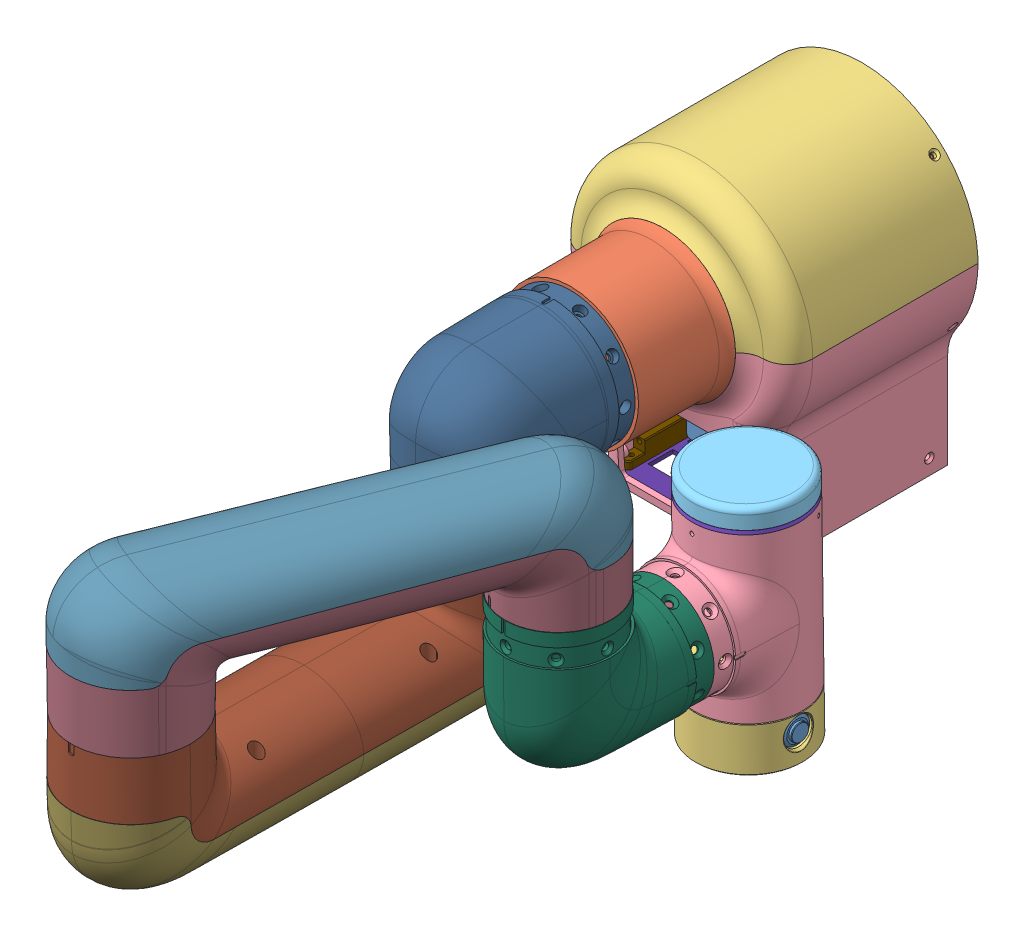
SolidWorks assembly PRO450包装版本, configuration 默认. Lengths in mm.
Overall size (276.89 209.51 434.16).
29 component instances, 22 part files, 10 mates.
Components (placement in the parent):
- J6末端^PRO450包装版本-1: J6末端^PRO450包装版本 [默认] at (339.7014 53.0863 383.1961) x (0.031889 0.000226 -0.999491) z (-0.999383 -0.01472 -0.031889) size (82.42 121.04 79.19) (virtual)
  - 复件 复件 按钮^J6末端_PRO450包装版本-1: 复件 复件 按钮^J6末端_PRO450包装版本 [默认] at (249.1515 73.2352 278.7054) x (0.374992 0.927026 -0.00197) z (-0.005254 0 -0.999986) size (14 14 21) (virtual)
  - 复件 复件 按钮六角螺母^J6末端_PRO450包装版本-1: 复件 复件 按钮六角螺母^J6末端_PRO450包装版本 [默认] at (249.0701 73.2352 263.2056) x (0.866013 -0.5 -0.00455) z (0.005254 0 0.999986) size (16 13.86 2.5) (virtual)
  - 复件 复件 按钮^J6末端_PRO450包装版本-2: 复件 复件 按钮^J6末端_PRO450包装版本 [默认] at (249.2251 73.2352 292.7052) x (0 -1 0) z (0.005254 0 0.999986) size (14 14 21) (virtual)
  - 复件 复件 按钮六角螺母^J6末端_PRO450包装版本-2: 复件 复件 按钮六角螺母^J6末端_PRO450包装版本 [默认] at (249.3065 73.2352 308.205) x (0 1 0) z (-0.005254 0 -0.999986) size (16 13.86 2.5) (virtual)
  - 复件 复件 PRO450_末端1-0^J6末端_PRO450包装版本-1: 复件 复件 PRO450_末端1-0^J6末端_PRO450包装版本 [默认] at (249.1883 60.2352 285.7053) x (0 1 0) z (-0.710812 0 -0.703382) size (31.65 56 56) (virtual)
  - 复件 复件 PRO450_J6关节^J6末端_PRO450包装版本-1: 复件 复件 PRO450_J6关节^J6末端_PRO450包装版本 [默认] at (249.1883 40.391 285.7053) x (-1 0 0) z (0 -1 0) size (70.87 56.29 85.54) (virtual)
  - 复件 复件 PRO450_末端盖1^J6末端_PRO450包装版本-1: 复件 复件 PRO450_末端盖1^J6末端_PRO450包装版本 [默认] at (249.1883 65.341 285.7053) x (0 0 1) z (0 -1 0) size (55.95 55.95 10.05) (virtual)
  - 复件 复件 灯环^J6末端_PRO450包装版本-1: 复件 复件 灯环^J6末端_PRO450包装版本 [默认] at (249.1883 -21.609 285.7053) x (-0.557927 0 -0.82989) z (0 1 0) size (52 52 2) (virtual)
  - 复件 复件 PRO450_末端2^J6末端_PRO450包装版本-1: 复件 复件 PRO450_末端2^J6末端_PRO450包装版本 [默认] at (249.1883 85.5852 285.7053) x (-0.703382 0 0.710812) z (0 1 0) size (54 54 3.1) (virtual)
  - 复件 复件 PRO450_J6亚克力^J6末端_PRO450包装版本-1: 复件 复件 PRO450_J6亚克力^J6末端_PRO450包装版本 [默认] at (249.1883 -21.609 285.7053) x (0 0 -1) z (0 -1 0) size (56 56 2) (virtual)
  - 复件 复件 PRO450_末端盖2^J6末端_PRO450包装版本-1: 复件 复件 PRO450_末端盖2^J6末端_PRO450包装版本 [默认] at (249.1883 -13.659 285.7053) x (0 0 1) z (0 -1 0) size (52.1 53.1 15.5) (virtual)
- 复件 PRO450_J2关节^PRO450包装版本-1: 复件 PRO450_J2关节^PRO450包装版本 [默认] at (-3.4123 69.4768 202.2089) x (-0.999975 -0.007101 0) z (0.007101 -0.999975 0) size (70.67 81.55 82.07) (virtual)
- J3^PRO450包装版本-1: J3^PRO450包装版本 [默认] at (169.8875 1.7298 308.2266) x (-0.507278 -0.003602 0.861775) z (-0.861753 -0.006119 -0.507291) size (243.34 74.06 177.46) (virtual)
  - 复件 复件 PRO450_J3关节^J3_PRO450包装版本-1: 复件 复件 PRO450_J3关节^J3_PRO450包装版本 [默认] at (-3.6963 61.9758 202.7089) x (0.866025 0 -0.5) z (-0.5 0 -0.866025) size (244.01 53.95 64.04) (virtual)
  - 复件 复件 PRO450_J3后壳^J3_PRO450包装版本-1: 复件 复件 PRO450_J3后壳^J3_PRO450包装版本 [默认] at (-3.6963 61.9758 202.7089) x (0.866025 0 -0.5) z (-0.5 0 -0.866025) size (243.48 46.55 63.1) (virtual)
- J4^PRO450包装版本-1: J4^PRO450包装版本 [默认] at (95.2435 0.6998 543.2233) x (-0.929005 -0.006597 -0.370009) z (0.369999 0.002627 -0.929028) size (63.26 94.83 233.13) (virtual)
  - 复件 复件 PRO450_J4关节^J4_PRO450包装版本-1: 复件 复件 PRO450_J4关节^J4_PRO450包装版本 [默认] at (152.1883 72.4758 285.7089) x (0 0 -1) z (1 0 0) size (233.04 46.72 63.1) (virtual)
  - 复件 复件 PRO450_J4后壳^J4_PRO450包装版本-1: 复件 复件 PRO450_J4后壳^J4_PRO450包装版本 [默认] at (152.1883 72.4758 285.7089) x (0 0 -1) z (1 0 0) size (232.78 87.06 63.26) (virtual)
- 复件 PRO450_J5关节^PRO450包装版本-1: 复件 PRO450_J5关节^PRO450包装版本 [默认] at (58.9721 84.9202 221.4806) x (0.031889 0.000226 -0.999491) z (-0.007101 0.999975 0) size (82.05 56.74 76.38) (virtual)
- J1底座^PRO450包装版本-1: J1底座^PRO450包装版本 [默认] at origin size (122 161.58 153.55) (virtual)
  - 复件 复件 底座板^J1底座_PRO450包装版本-1: 复件 复件 底座板^J1底座_PRO450包装版本 [默认] at (-3.6963 109.4758 -1.2911) x (-1 0 0) z (0 0 1) size (96 146 3) (virtual)
  - 复件 复件 底座面板^J1底座_PRO450包装版本-1: 复件 复件 底座面板^J1底座_PRO450包装版本 [默认] at (38.3037 9.477 -1.2911) x (-1 0 0) z (0 1 0) size (84 92.5 2) (virtual)
  - 复件 复件 底座PCB固定支架^J1底座_PRO450包装版本-1: 复件 复件 底座PCB固定支架^J1底座_PRO450包装版本 [默认] at (-37.7873 11.477 1.1089) x (0 1 0) z (0 0 1) size (105 10 86.5) (virtual)
  - 复件 复件 底座PCB固定支架^J1底座_PRO450包装版本-2: 复件 复件 底座PCB固定支架^J1底座_PRO450包装版本 [默认] at (36.2127 11.477 1.1089) x (0 1 0) z (0 0 1) size (105 10 86.5) (virtual)
  - 复件 复件 PCB-2^J1底座_PRO450包装版本-1: 复件 复件 PCB-2^J1底座_PRO450包装版本 [默认] at (36.3037 12.977 58.0589) x (-1 0 0) z (0 0 -1) size (80 103.27 23.5) (virtual)
  - 复件 复件 套筒_stp5057^J1底座_PRO450包装版本-1: 复件 复件 套筒_stp5057^J1底座_PRO450包装版本 [默认] at (-3.6963 109.477 65.2089) x (1 0 0) z (0 -1 0) size (116 153.5 105) (virtual)
  - 复件 复件 底座壳1^J1底座_PRO450包装版本-1: 复件 复件 底座壳1^J1底座_PRO450包装版本 [默认] at (-3.6963 109.477 -1.2911) x (0 -1 0) z (0 0 1) size (61 122 104.69) (virtual)
  - 复件 复件 底座壳2^J1底座_PRO450包装版本-1: 复件 复件 底座壳2^J1底座_PRO450包装版本 [默认] at (-3.6963 109.477 -1.2911) x (0 -1 0) z (0 0 1) size (102.58 122 104.74) (virtual)
Mates (geometry in assembly coordinates):
- 重合5: coincident: plane of 复件 PRO450_J2关节^PRO450包装版本-1 through (37.1864 62.7649 170.7089) normal (0.007101 -0.999975 0); plane of J3^PRO450包装版本-1/复件 复件 PRO450_J3关节^J3_PRO450包装版本-1 through (17.6703 62.6263 223.6004) normal (-0.007101 0.999975 0)
- 同心2: concentric: cylinder of J3^PRO450包装版本-1/复件 复件 PRO450_J3关节^J3_PRO450包装版本-1 through (-4.8816 62.4662 382.2025) axis (-0.007101 0.999975 0) radius 20.5; cylinder of J4^PRO450包装版本-1/复件 复件 PRO450_J4关节^J4_PRO450包装版本-1 through (-4.9845 76.9658 382.2025) axis (0.007101 -0.999975 0) radius 7.5
- 重合6: coincident: plane of J3^PRO450包装版本-1/复件 复件 PRO450_J3关节^J3_PRO450包装版本-1 through (16.1229 66.6155 403.594) normal (-0.007101 0.999975 0); plane of J4^PRO450包装版本-1/复件 复件 PRO450_J4关节^J4_PRO450包装版本-1 through (-16.504 66.3838 354.5335) normal (0.007101 -0.999975 0)
- 同心3: concentric: cylinder of J4^PRO450包装版本-1/复件 复件 PRO450_J4关节^J4_PRO450包装版本-1 through (59.0289 76.9204 221.4806) axis (0.007101 -0.999975 0) radius 16; cone of 复件 PRO450_J5关节^PRO450包装版本-1 through (59.1106 65.4206 221.4806) axis (0.007101 -0.999975 0)
- 重合7: coincident: plane of J4^PRO450包装版本-1/复件 复件 PRO450_J4关节^J4_PRO450包装版本-1 through (48.8293 72.8478 197.0341) normal (0.007101 -0.999975 0); plane of 复件 PRO450_J5关节^PRO450包装版本-1 through (101.0249 73.2185 222.8197) normal (-0.007101 0.999975 0)
- 重合10: coincident: plane of J6末端^PRO450包装版本-1/复件 复件 PRO450_J6关节^J6末端_PRO450包装版本-1 through (61.358 8.5407 167.5119) normal (-0.031889 -0.000226 0.999491); plane of 复件 PRO450_J5关节^PRO450包装版本-1 through (102.6617 85.2304 168.8471) normal (0.031889 0.000226 -0.999491)
- 同心5: concentric: cone of 复件 PRO450_J2关节^PRO450包装版本-1 through (-3.4497 74.7507 202.2089) axis (-0.007101 0.999975 0); cylinder of J3^PRO450包装版本-1/复件 复件 PRO450_J3关节^J3_PRO450包装版本-1 through (-3.1822 37.0776 202.2089) axis (-0.007101 0.999975 0) radius 7.5
- 同心6: concentric: cylinder of J6末端^PRO450包装版本-1/复件 复件 PRO450_J6关节^J6末端_PRO450包装版本-1 through (61.1165 24.944 167.508) axis (-0.031889 -0.000226 0.999491) radius 27; cylinder of 复件 PRO450_J5关节^PRO450包装版本-1 through (61.0208 24.9433 170.5064) axis (0.031889 0.000226 -0.999491) radius 27.0102
- 同心7: concentric: cylinder of 复件 PRO450_J2关节^PRO450包装版本-1 through (-3.6963 109.4758 152.2089) axis (0 0 -1) radius 34; cylinder of J1底座^PRO450包装版本-1/复件 复件 套筒_stp5057^J1底座_PRO450包装版本-1 through (-3.6963 109.4758 104.7089) axis (0 0 -1) radius 35.82
- 重合11: coincident: plane of 复件 PRO450_J2关节^PRO450包装版本-1 through (37.7867 69.7694 152.2089) normal (0 0 -1); plane of J1底座^PRO450包装版本-1/复件 复件 套筒_stp5057^J1底座_PRO450包装版本-1 through (-3.6963 139.477 152.2089) normal (0 0 1)
